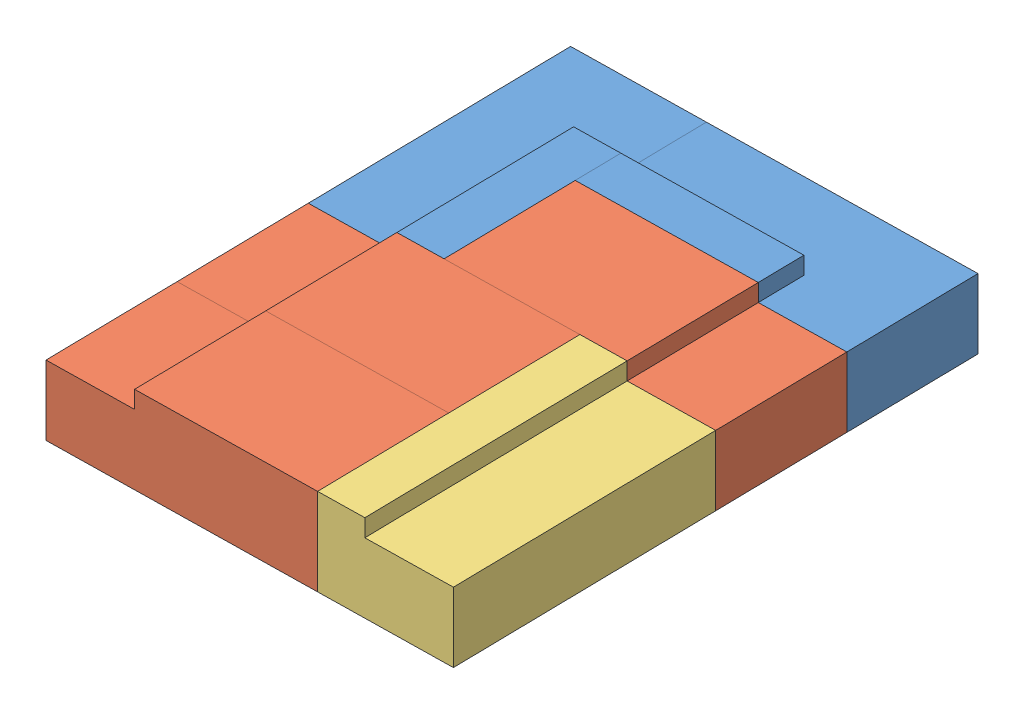
SolidWorks assembly Bottom-top-uncut, configuration Default. Lengths in mm.
Overall size (352.98 75 465.95).
6 component instances, 3 part files, 10 mates.
Components (placement in the parent):
- Brick-Sharp-BackLeftCut-1: Brick-Sharp-BackLeftCut [Default] at (-84.1473 -135.3254 -303.3983) x (-0.999848 0 0.017452) z (-0.017452 0 -0.999848) size (230 75 115)
- Brick-Sharp-BackCut-1: Brick-Sharp-BackCut [Default] at (-82.1403 -135.3254 -188.4158) x (-0.999848 0 0.017452) z (-0.017452 0 -0.999848) size (230 75 115)
- Brick-Sharp-BackLeftCut-2: Brick-Sharp-BackLeftCut [Default] at (-255.6175 -135.3254 -242.8965) x (0.017452 0 0.999848) z (-0.999848 0 0.017452) size (230 75 115)
- Brick-Sharp-BackCut-2: Brick-Sharp-BackCut [Default] at (-195.1157 -135.3254 -71.4263) x (0.999848 0 -0.017452) z (0.017452 0 0.999848) size (230 75 115)
- Brick-Sharp-BackCut-3: Brick-Sharp-BackCut [Default] at (-193.1087 -135.3254 43.5562) x (0.999848 0 -0.017452) z (0.017452 0 0.999848) size (230 75 115)
- Brick-Sharp-SideCut-1: Brick-Sharp-SideCut [Default] at (-21.6385 -135.3254 -16.9456) x (0.017452 0 0.999848) z (-0.999848 0 0.017452) size (230 75 115)
Mates (geometry in assembly coordinates):
- Coincident1: coincident anti-aligned: plane of Brick-Sharp-BackLeftCut-1 through (31.8387 -97.8254 -247.9141) normal (0.017452 0 0.999848); plane of Brick-Sharp-BackCut-1 through (31.8387 -97.8254 -247.9141) normal (-0.017452 0 -0.999848)
- Coincident2: coincident aligned: line of Brick-Sharp-BackLeftCut-1 through (31.8387 -112.8254 -247.9141) axis (-0.017452 0 -0.999848); line of Brick-Sharp-BackCut-1 through (33.8457 -112.8254 -132.9316) axis (-0.017452 0 -0.999848)
- Coincident10: coincident anti-aligned: plane of Brick-Sharp-BackCut-1 through (-196.1192 -97.8254 -128.9175) normal (-0.999848 0 0.017452); plane of Brick-Sharp-BackLeftCut-2 through (-200.1333 -97.8254 -358.8825) normal (0.999848 0 -0.017452)
- Coincident11: coincident aligned: line of Brick-Sharp-BackLeftCut-1 through (29.8317 -172.8254 -362.8966) axis (-0.999848 0 0.017452); line of Brick-Sharp-BackLeftCut-2 through (-200.1333 -172.8254 -358.8825) axis (-0.999848 0 0.017452)
- Coincident12: coincident anti-aligned: plane of Brick-Sharp-BackLeftCut-2 through (-196.1192 -97.8254 -128.9175) normal (0.017452 0 0.999848); plane of Brick-Sharp-BackCut-2 through (-311.1017 -97.8254 -126.9105) normal (-0.017452 0 -0.999848)
- Coincident13: coincident aligned: line of Brick-Sharp-BackLeftCut-2 through (-315.1158 -172.8254 -356.8755) axis (0.017452 0 0.999848); line of Brick-Sharp-BackCut-2 through (-311.1017 -172.8254 -126.9105) axis (0.017452 0 0.999848)
- Coincident14: coincident anti-aligned: plane of Brick-Sharp-BackCut-2 through (-309.0947 -97.8254 -11.928) normal (0.017452 0 0.999848); plane of Brick-Sharp-BackCut-3 through (-309.0947 -97.8254 -11.928) normal (-0.017452 0 -0.999848)
- Coincident15: coincident aligned: line of Brick-Sharp-BackCut-2 through (-311.1017 -172.8254 -126.9105) axis (0.017452 0 0.999848); line of Brick-Sharp-BackCut-3 through (-309.0947 -172.8254 -11.928) axis (0.017452 0 0.999848)
- Coincident16: coincident anti-aligned: plane of Brick-Sharp-BackCut-3 through (-79.1297 -97.8254 -15.9421) normal (0.999848 0 -0.017452); plane of Brick-Sharp-SideCut-1 through (-81.1367 -97.8254 -130.9246) normal (-0.999848 0 0.017452)
- Coincident17: coincident anti-aligned: line of Brick-Sharp-BackCut-1 through (-196.1192 -172.8254 -128.9175) axis (0.999848 0 -0.017452); line of Brick-Sharp-SideCut-1 through (33.8457 -172.8254 -132.9316) axis (-0.999848 0 0.017452)
